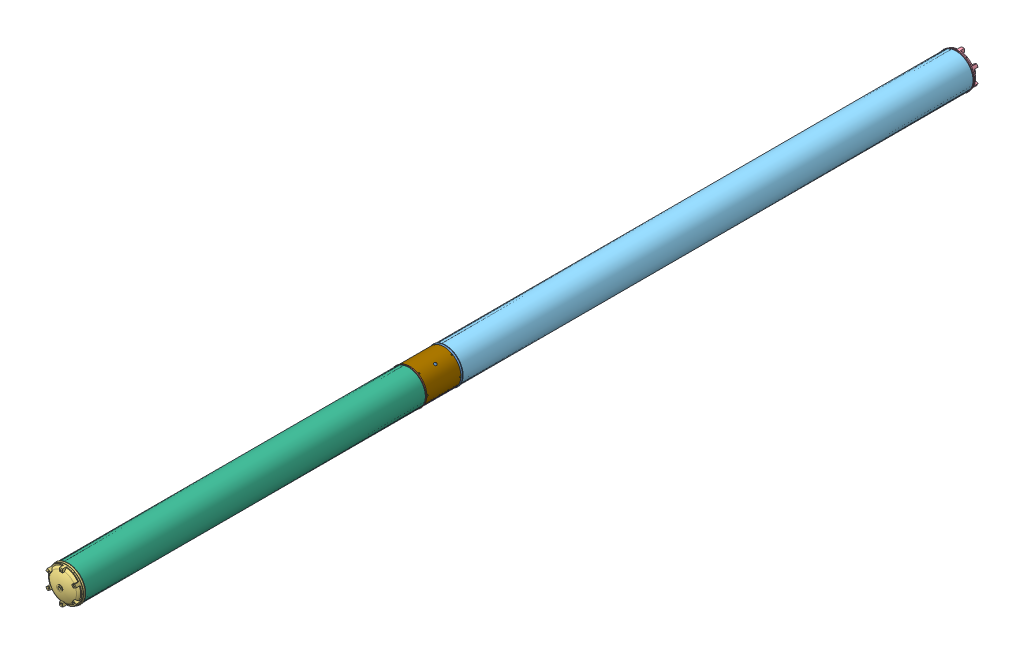
SolidWorks assembly 10012-R02_PROPELLANT_TANK_ASSEMBLY, configuration Default. Lengths in mm.
Overall size (426.77 426.77 8102.6).
20 component instances, 9 part files, 30 mates.
Components (placement in the parent):
- 14002-R08_LOX_BULKHEAD_LOWER-1: 14002-R08_LOX_BULKHEAD_LOWER [Default] at (0 0 4546.6) x (-1 0 0) z (0 0 -1) size (312.42 312.42 96.52)
- 14002-R08_RP1_BULKHEAD_UPPER-1: 14002-R08_RP1_BULKHEAD_UPPER [Default] at (0 0 4902.2) x (0.5 0.866025 0) z (0 0 1) size (312.42 312.42 96.52)
- 14002-R09_RP1_BULKHEAD_LOWER-1: 14002-R09_RP1_BULKHEAD_LOWER [Default] at (0 0 7924.8) x (-1 0 0) z (0 0 -1) size (312.42 312.42 88.9)
- 14004-R09_LOX_BULKHEAD-1: 14004-R09_LOX_BULKHEAD [Default] at origin size (312.42 312.42 88.9)
- 14005-R05_LOX_TANK_WALL-1: 14005-R05_LOX_TANK_WALL [Default] at (0 0 -12.7) x (0 0 1) z (0 1 0) size (4572 304.8 304.8)
- 14006-R05_RP-1_TANK_WALL-1: 14006-R05_RP-1_TANK_WALL [Default] at (0 0 7937.5) x (0 0 -1) z (0 -1 0) size (3048 304.8 304.8)
- 92949A560_18-8 SS BUTTON-HEAD SOCKET CAP SCREW-13: 92949A560_18-8 SS BUTTON-HEAD SOCKET CAP SCREW [92949A560] at (-77.8764 -134.8859 4870.45) x (0.620362 -0.358166 0.697759) z (-0.5 -0.866025 0) size (11.1 11.1 13.42)
- 92949A560_18-8 SS BUTTON-HEAD SOCKET CAP SCREW-14: 92949A560_18-8 SS BUTTON-HEAD SOCKET CAP SCREW [92949A560] at (-77.8764 -134.8859 4578.35) x (0.863118 -0.498321 0.081879) z (-0.5 -0.866025 0) size (11.1 11.1 13.42)
- Propellant_Tank_Split_Airframe_RP1FillLOXExit-2: Propellant_Tank_Split_Airframe_RP1FillLOXExit [Default] at (0 0 4572) x (0.866025 -0.5 0) z (-0.5 -0.866025 0) size (304.8 304.8 178.31)
- Propellant_Tank_Split_Airframe_HeIn-3: Propellant_Tank_Split_Airframe_HeIn [Default] at (0 0 4572) x (-0.866025 0.5 0) z (0.5 0.866025 0) size (304.8 304.8 178.31)
- 92949A560_18-8 SS BUTTON-HEAD SOCKET CAP SCREW-25: 92949A560_18-8 SS BUTTON-HEAD SOCKET CAP SCREW [92949A560] at (77.8764 -134.8859 4578.35) x (0.863118 0.498321 0.081879) z (0.5 -0.866025 0) size (11.1 11.1 13.42)
- 92949A560_18-8 SS BUTTON-HEAD SOCKET CAP SCREW-26: 92949A560_18-8 SS BUTTON-HEAD SOCKET CAP SCREW [92949A560] at (155.7528 0 4578.35) x (0 0.996642 0.081879) z (1 0 0) size (11.1 11.1 13.42)
- 92949A560_18-8 SS BUTTON-HEAD SOCKET CAP SCREW-27: 92949A560_18-8 SS BUTTON-HEAD SOCKET CAP SCREW [92949A560] at (77.8764 134.8859 4578.35) x (-0.863118 0.498321 0.081879) z (0.5 0.866025 0) size (11.1 11.1 13.42)
- 92949A560_18-8 SS BUTTON-HEAD SOCKET CAP SCREW-28: 92949A560_18-8 SS BUTTON-HEAD SOCKET CAP SCREW [92949A560] at (-77.8764 134.8859 4578.35) x (-0.863118 -0.498321 0.081879) z (-0.5 0.866025 0) size (11.1 11.1 13.42)
- 92949A560_18-8 SS BUTTON-HEAD SOCKET CAP SCREW-29: 92949A560_18-8 SS BUTTON-HEAD SOCKET CAP SCREW [92949A560] at (-155.7528 0 4578.35) x (0 -0.996642 0.081879) z (-1 0 0) size (11.1 11.1 13.42)
- 92949A560_18-8 SS BUTTON-HEAD SOCKET CAP SCREW-30: 92949A560_18-8 SS BUTTON-HEAD SOCKET CAP SCREW [92949A560] at (77.8764 -134.8859 4870.45) x (0.620362 0.358166 0.697759) z (0.5 -0.866025 0) size (11.1 11.1 13.42)
- 92949A560_18-8 SS BUTTON-HEAD SOCKET CAP SCREW-31: 92949A560_18-8 SS BUTTON-HEAD SOCKET CAP SCREW [92949A560] at (155.7528 0 4870.45) x (0 0.716332 0.697759) z (1 0 0) size (11.1 11.1 13.42)
- 92949A560_18-8 SS BUTTON-HEAD SOCKET CAP SCREW-32: 92949A560_18-8 SS BUTTON-HEAD SOCKET CAP SCREW [92949A560] at (77.8764 134.8859 4870.45) x (-0.620362 0.358166 0.697759) z (0.5 0.866025 0) size (11.1 11.1 13.42)
- 92949A560_18-8 SS BUTTON-HEAD SOCKET CAP SCREW-33: 92949A560_18-8 SS BUTTON-HEAD SOCKET CAP SCREW [92949A560] at (-77.8764 134.8859 4870.45) x (-0.620362 -0.358166 0.697759) z (-0.5 0.866025 0) size (11.1 11.1 13.42)
- 92949A560_18-8 SS BUTTON-HEAD SOCKET CAP SCREW-34: 92949A560_18-8 SS BUTTON-HEAD SOCKET CAP SCREW [92949A560] at (-155.7528 0 4870.45) x (0 -0.716332 0.697759) z (-1 0 0) size (11.1 11.1 13.42)
Mates (geometry in assembly coordinates):
- Coincident1: coincident: plane of 14004-R09_LOX_BULKHEAD-1 through (0 0 0) normal (0 0 1); plane of assembly through (0 0 0) normal (0 0 1)
- Coincident2: coincident: plane of 14004-R09_LOX_BULKHEAD-1 through (0 0 0) normal (0 1 0); plane of assembly through (0 0 0) normal (0 1 0)
- Coincident3: coincident: plane of 14004-R09_LOX_BULKHEAD-1 through (0 0 0) normal (1 0 0); plane of assembly through (0 0 0) normal (1 0 0)
- Concentric1: concentric: cylinder of 14004-R09_LOX_BULKHEAD-1 through (0 0 -78.7237) axis (0 0 1) radius 148.59; cylinder of 14005-R05_LOX_TANK_WALL-1 through (0 0 4559.3) axis (0 0 -1) radius 152.4
- Coincident4: coincident: plane of 14004-R09_LOX_BULKHEAD-1 through (0 0 -12.7) normal (0 0 1); plane of 14005-R05_LOX_TANK_WALL-1 through (0 0 -12.7) normal (0 0 -1)
- Parallel3: parallel: plane of 14005-R05_LOX_TANK_WALL-1 through (0 0 -12.7) normal (0 1 0); plane of assembly through (0 0 0) normal (0 1 0)
- Coincident8: coincident: plane of 14002-R08_LOX_BULKHEAD_LOWER-1 through (0 0 4559.3) normal (0 0 -1); plane of 14005-R05_LOX_TANK_WALL-1 through (0 0 4559.3) normal (0 0 1)
- Concentric2: concentric: cylinder of 14002-R08_LOX_BULKHEAD_LOWER-1 through (0 0 4625.3237) axis (0 0 -1) radius 148.59; cylinder of 14005-R05_LOX_TANK_WALL-1 through (0 0 4559.3) axis (0 0 -1) radius 152.4
- Parallel4: parallel: plane of 14002-R08_LOX_BULKHEAD_LOWER-1 through (0 0 4546.6) normal (0 0 -1); plane of assembly through (0 0 0) normal (0 0 1)
- Parallel5: parallel: plane of 14002-R08_LOX_BULKHEAD_LOWER-1 through (0 0 4546.6) normal (0 1 0); plane of assembly through (0 0 0) normal (0 1 0)
- Coincident13: coincident: plane of 14002-R08_RP1_BULKHEAD_UPPER-1 through (0 0 4889.5) normal (0 0 1); plane of 14006-R05_RP-1_TANK_WALL-1 through (0 0 4889.5) normal (0 0 -1)
- Concentric5: concentric: cylinder of 14002-R08_RP1_BULKHEAD_UPPER-1 through (0 0 4823.4763) axis (0 0 1) radius 148.59; cylinder of 14006-R05_RP-1_TANK_WALL-1 through (0 0 4889.5) axis (0 0 1) radius 152.4
- Parallel6: parallel: plane of 14006-R05_RP-1_TANK_WALL-1 through (0 0 7937.5) normal (0 -1 0); plane of assembly through (0 0 0) normal (0 1 0)
- Parallel7: parallel: plane of 14006-R05_RP-1_TANK_WALL-1 through (0 0 7937.5) normal (0 0 -1); plane of assembly through (0 0 0) normal (0 0 1)
- Coincident15: coincident: plane of 14002-R09_RP1_BULKHEAD_LOWER-1 through (0 0 7937.5) normal (0 0 -1); plane of 14006-R05_RP-1_TANK_WALL-1 through (0 0 7937.5) normal (0 0 1)
- Concentric6: concentric: cylinder of 14002-R09_RP1_BULKHEAD_LOWER-1 through (0 0 8003.5237) axis (0 0 -1) radius 148.59; cylinder of 14006-R05_RP-1_TANK_WALL-1 through (0 0 4889.5) axis (0 0 1) radius 152.4
- Parallel8: parallel: plane of 14002-R09_RP1_BULKHEAD_LOWER-1 through (0 0 7924.8) normal (0 0 -1); plane of assembly through (0 0 0) normal (0 0 1)
- Coincident17: coincident: plane of 14002-R09_RP1_BULKHEAD_LOWER-1 through (0 0 7924.8) normal (0 1 0); plane of assembly through (0 0 0) normal (0 1 0)
- Concentric12: concentric: circle of 92949A560_18-8 SS BUTTON-HEAD SOCKET CAP SCREW-13; cylinder of 14002-R08_RP1_BULKHEAD_UPPER-1 through (-74.6125 -129.2326 4870.45) axis (-0.5 -0.866025 0) radius 3.175
- Concentric13: concentric: cylinder of 14002-R08_LOX_BULKHEAD_LOWER-1 through (-74.6125 -129.2326 4578.35) axis (-0.5 -0.866025 0) radius 3.175; circle of 92949A560_18-8 SS BUTTON-HEAD SOCKET CAP SCREW-14
- Concentric15: concentric: circle of 14002-R08_LOX_BULKHEAD_LOWER-1; circle of Propellant_Tank_Split_Airframe_RP1FillLOXExit-2
- Concentric16: concentric: cylinder of 14002-R08_RP1_BULKHEAD_UPPER-1 through (74.6125 -129.2326 4870.45) axis (0.5 -0.866025 0) radius 3.175; cylinder of Propellant_Tank_Split_Airframe_RP1FillLOXExit-2 through (103.0605 -178.506 4870.45) axis (-0.5 0.866025 0) radius 3.175
- Concentric17: concentric: cylinder of 14002-R08_RP1_BULKHEAD_UPPER-1 through (74.6125 -129.2326 4870.45) axis (0.5 -0.866025 0) radius 3.175; cylinder of Propellant_Tank_Split_Airframe_RP1FillLOXExit-2 through (103.0605 -178.506 4870.45) axis (-0.5 0.866025 0) radius 3.175
- Concentric18: concentric: cylinder of 14002-R08_RP1_BULKHEAD_UPPER-1 through (-74.6125 -129.2326 4870.45) axis (-0.5 -0.866025 0) radius 3.175; cylinder of Propellant_Tank_Split_Airframe_RP1FillLOXExit-2 through (-103.0605 -178.506 4870.45) axis (0.5 0.866025 0) radius 3.175
- Concentric19: concentric: cylinder of 14002-R08_LOX_BULKHEAD_LOWER-1 through (-149.225 0 4578.35) axis (-1 0 0) radius 3.175; cylinder of Propellant_Tank_Split_Airframe_RP1FillLOXExit-2 through (-206.121 0 4578.35) axis (1 0 0) radius 3.175
- Coincident20: coincident: line of Propellant_Tank_Split_Airframe_RP1FillLOXExit-2 through (131.9823 -76.2 4876.8) axis (0 0 -1); line of Propellant_Tank_Split_Airframe_HeIn-3 through (131.9823 -76.2 4876.8) axis (0 0 -1)
- Coincident21: coincident: line of Propellant_Tank_Split_Airframe_RP1FillLOXExit-2 through (-131.9823 76.2 4876.8) axis (0 0 -1); line of Propellant_Tank_Split_Airframe_HeIn-3 through (-131.9823 76.2 4876.8) axis (0 0 -1)
- Concentric24: concentric: cylinder of Propellant_Tank_Split_Airframe_RP1FillLOXExit-2 through (-75.7355 53.0306 4838.7) axis (-0.819152 0.573576 0) radius 3.175; cylinder of Propellant_Tank_Split_Airframe_HeIn-3 through (-114.4355 80.1286 4838.7) axis (-0.819152 0.573576 0) radius 3.175
- Tangent1: tangent: plane of 92949A560_18-8 SS BUTTON-HEAD SOCKET CAP SCREW-14 through (-75.8065 -132.2095 4572.8187) normal (0.5 0.866025 0); cylinder of Propellant_Tank_Split_Airframe_RP1FillLOXExit-2 through (0 0 4876.8) axis (0 0 -1) radius 152.4
- Tangent2: tangent: plane of 92949A560_18-8 SS BUTTON-HEAD SOCKET CAP SCREW-13 through (-72.8463 -133.9185 4866.4744) normal (0.5 0.866025 0); cylinder of Propellant_Tank_Split_Airframe_RP1FillLOXExit-2 through (0 0 4876.8) axis (0 0 -1) radius 152.4
